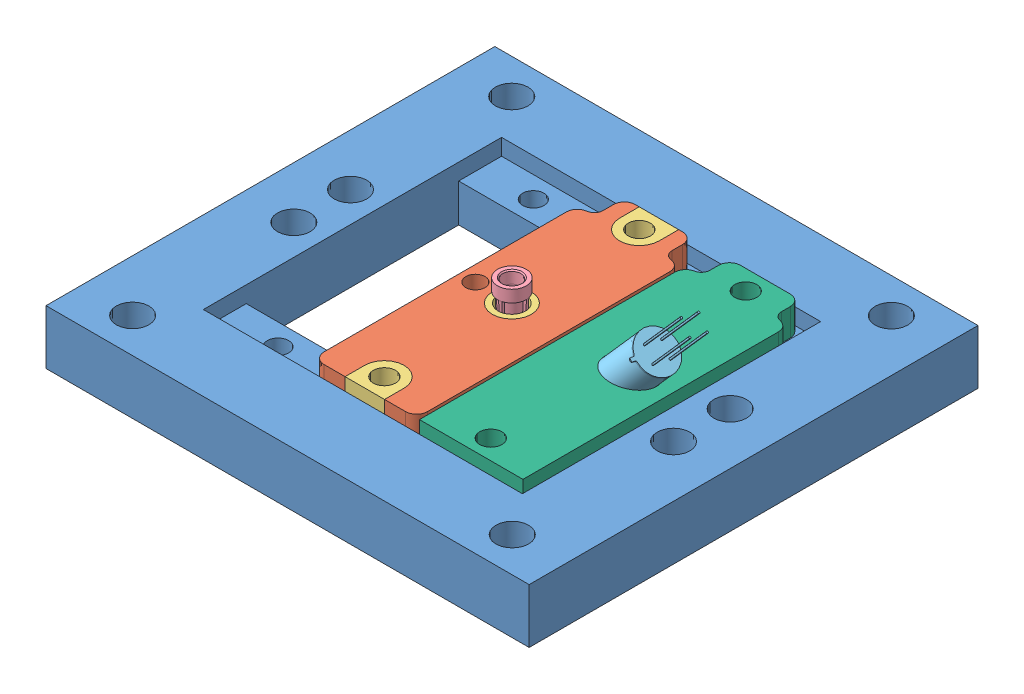
SolidWorks assembly Mount and Gantries, configuration Default. Lengths in mm.
Overall size (112.65 65.26 104.65).
7 component instances, 6 part files, 8 mates.
Components (placement in the parent):
- New Mount-1: New Mount [Default] at origin size (112.65 12.7 104.65)
- New Mount Needle holder Assembly r1-1: New Mount Needle holder Assembly r1 [Default] at (44.276 8.89 -17.987) size (62.62 32.93 68.58)
  - New Mount Needle holder standard r1-1: New Mount Needle holder standard r1 [Default] at origin size (24.28 22.21 68.58)
  - New Mount Needle holder conductive r1-1: New Mount Needle holder conductive r1 [Default] at origin size (9.2 24.22 68.58)
  - Qosina 11077-1: Qosina 11077 [Default] at (12.065 -19.86 -34.29) x (0.149921 0 0.988698) z (0 1 0) size (55 55 32.93)
- MLX90614ACF-1: MLX90614ACF [Default] at (78.8635 9.4824 -52.279) x (-0.619313 0.547921 0.562347) z (0.421173 -0.372622 0.826901) size (9.12 75.92 9.12)
- IR sensor mount-1: IR sensor mount [Default] at (69.0833 8.89 -86.569) x (0 0 1) z (-1 0 0) size (68.58 6.35 24.13)
Mates (geometry in assembly coordinates):
- Coincident3: coincident anti-aligned: plane of New Mount-1 through (0 8.89 0) normal (0 1 0); plane of New Mount Needle holder Assembly r1-1/New Mount Needle holder standard r1-1 through (44.276 8.89 -17.987) normal (0 -1 0)
- Concentric2: concentric anti-aligned: cylinder of New Mount-1 through (56.341 8.89 -22.559) axis (0 -1 0) radius 2.5; cylinder of New Mount Needle holder Assembly r1-1/New Mount Needle holder conductive r1-1 through (56.341 -8.971 -22.559) axis (0 1 0) radius 2.6
- Parallel2: parallel anti-aligned: plane of New Mount-1 through (0 12.7 -17.559) normal (0 0 -1); plane of New Mount Needle holder Assembly r1-1/New Mount Needle holder standard r1-1 through (44.276 15.24 -17.987) normal (0 0 1)
- Coincident10: coincident anti-aligned: plane of New Mount-1 through (0 8.89 0) normal (0 1 0); plane of IR sensor mount-1 through (69.0833 8.89 -86.569) normal (0 -1 0)
- Concentric6: concentric aligned: cylinder of New Mount-1 through (81.1483 8.89 -22.559) axis (0 -1 0) radius 2.5; cylinder of IR sensor mount-1 through (81.1483 15.24 -22.559) axis (0 -1 0) radius 2.6
- Parallel4: parallel anti-aligned: plane of New Mount-1 through (93.519 12.7 0) normal (-1 0 0); plane of IR sensor mount-1 through (93.2133 15.24 -86.569) normal (1 0 0)
- Concentric7: concentric anti-aligned: cylinder of MLX90614ACF-1 through (71.1908 0.81 -52.279) axis (-0.66262 -0.748956 0) radius 4.5; cylinder of IR sensor mount-1 through (74.2744 4.2954 -52.279) axis (0.66262 0.748956 0) radius 4.55
- Distance4: distance = 40 mm: point of MLX90614ACF-1; plane of IR sensor mount-1 through (69.0833 15.24 -86.569) normal (0 1 0)
